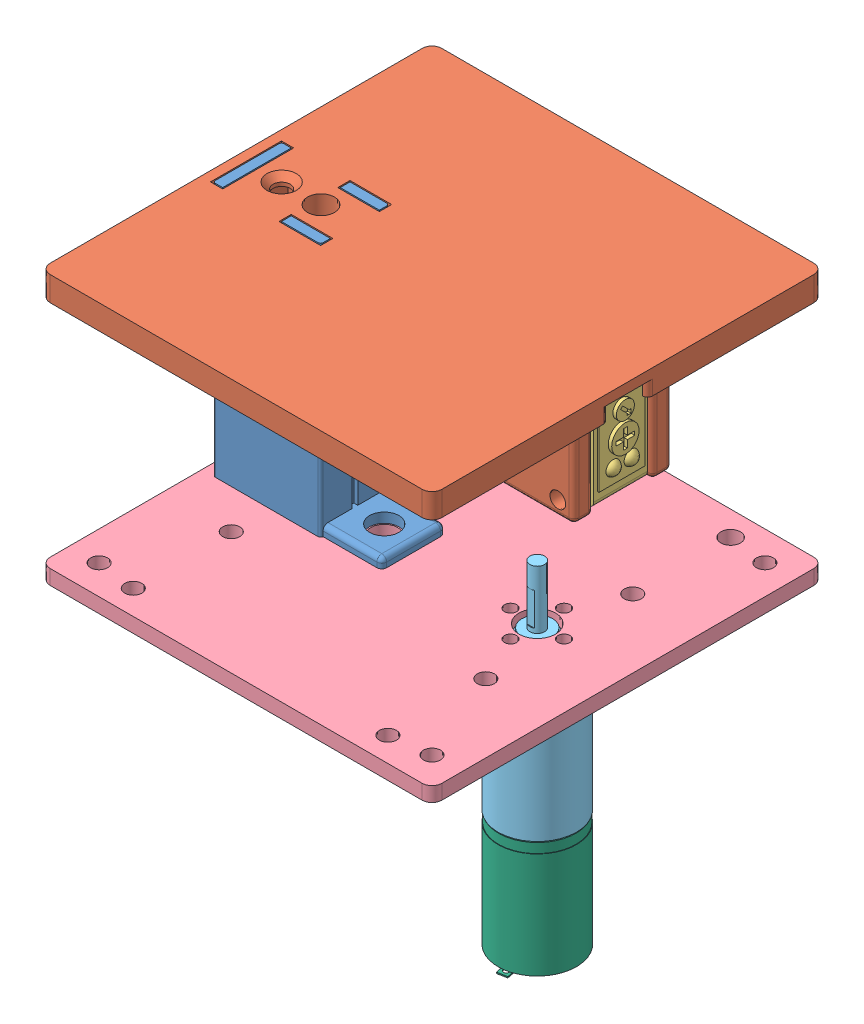
SolidWorks assembly Balise_principale, configuration Default. Lengths in mm.
Overall size (80 109.7 80).
12 component instances, 9 part files, 12 mates.
Components (placement in the parent):
- Pilier_top_sick-1: Pilier_top_sick [Default] at (-9.2487 63.12 67.5253) size (80 52 80)
  - Pilier-1: Pilier [Default] at (-7.3604 -4.447 58.7428) size (34 52 14)
  - Plaque_top_SICK-1: Plaque_top_SICK [Default] at (-9.6075 42.553 91.7428) size (80 21 80)
    - Plaque_top-2: Plaque_top [Default] at origin size (80 21 80)
    - SICK WL100-N4439-Bestell-Nr_6028604(0)-1-1: SICK WL100-N4439-Bestell-Nr_6028604(0)-1 [Default] at (50.3 -13 -45.5) x (0 1 0) z (0 0 -1) size (20 42.65 11)
- Plaque_bottom-1: Plaque_bottom [Default] at (-18.8562 55.673 159.2681) size (80 3 80)
- minimotor_1624_155-1: minimotor_1624_155 [Default] at (36.6695 13.1341 137.6385) x (1 0 0) z (0 1 0) size (19.2 20.94 68.9)
  - 15_5 3stages-1: 15_5 3stages [Default] at (5.9744 18.3704 42.539) size (16 16 44.1)
  - 1624S-1: 1624S [Default] at (5.9744 18.3704 -12.161) x (0.192236 -0.981349 0) z (0 0 1) size (18.2 16 32.9)
- Profilé Aluminium Rexroth 20x20 L38-1: Profilé Aluminium Rexroth 20x20 L38 [Default] at (11.3938 17.673 119.2681) size (20 38 20) (hidden)
- mirror-1: mirror [Default] at (61.7446 62.373 120.9231) x (-0.552942 0 -0.83322) z (0.83322 0 -0.552942) size (21.94 20.46 30) (hidden)
- Interface_v1-1: Interface_v1 [Default] at (-8.8562 52.673 158.2681) size (60 3 28) (hidden)
Mates (geometry in assembly coordinates):
- Coincident1: coincident anti-aligned: plane of Pilier_top_sick-1/Pilier-1 through (-16.6091 58.673 126.2681) normal (0 -1 0); plane of Plaque_bottom-1 through (-18.8562 58.673 159.2681) normal (0 1 0)
- Concentric1: concentric aligned: circle of Pilier_top_sick-1/Plaque_top_SICK-1/Plaque_top-2; circle of Plaque_bottom-1
- Coincident2: coincident anti-aligned: plane of Plaque_bottom-1 through (-18.8562 55.673 159.2681) normal (0 -1 0); plane of minimotor_1624_155-1/15_5 3stages-1 through (42.6438 55.673 125.0181) normal (0 1 0)
- Concentric2: concentric anti-aligned: circle of Plaque_bottom-1; circle of minimotor_1624_155-1/15_5 3stages-1
- Concentric3: concentric aligned: circle of Plaque_bottom-1; circle of Profilé Aluminium Rexroth 20x20 L38-1
- Coincident3: coincident anti-aligned: plane of Plaque_bottom-1 through (-18.8562 55.673 159.2681) normal (0 -1 0); plane of Profilé Aluminium Rexroth 20x20 L38-1 through (11.3938 55.673 115.2681) normal (0 1 0)
- Coincident4: coincident anti-aligned: plane of minimotor_1624_155-1/15_5 3stages-1 through (42.6438 69.873 120.0181) normal (0 1 0); plane of mirror-1 through (42.6438 69.873 119.2681) normal (0 -1 0)
- Concentric4: concentric aligned: circle of minimotor_1624_155-1/15_5 3stages-1; circle of mirror-1
- Coincident6: coincident anti-aligned: plane of Plaque_bottom-1 through (-18.8562 55.673 159.2681) normal (0 -1 0); plane of Interface_v1-1 through (-8.8562 55.673 158.2681) normal (0 1 0)
- Concentric6: concentric aligned: circle of Plaque_bottom-1; circle of Interface_v1-1
- Concentric7: concentric aligned: circle of Plaque_bottom-1; circle of Interface_v1-1
- Parallel1: parallel aligned: line of Pilier_top_sick-1/Plaque_top_SICK-1/Plaque_top-2 through (-16.8562 105.673 159.2681) axis (1 0 0); line of Plaque_bottom-1 through (-16.8562 55.673 159.2681) axis (1 0 0)
